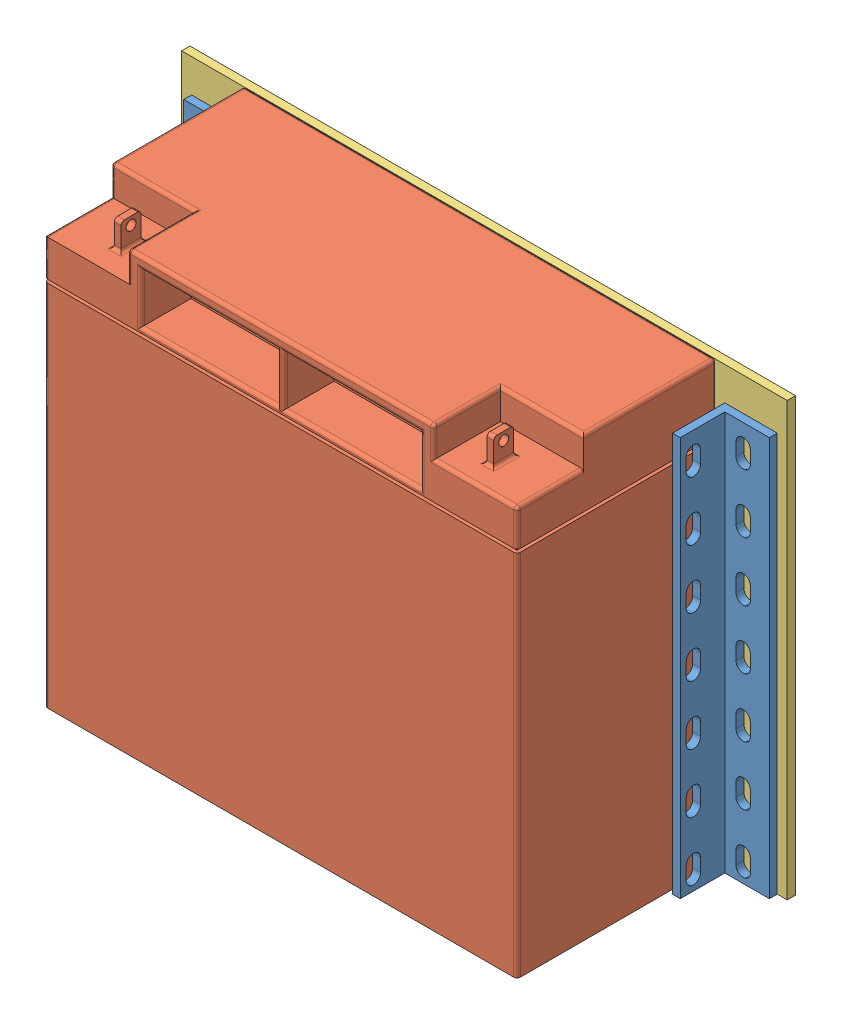
SolidWorks assembly 2018-204-Battery, configuration Default. Lengths in mm.
Overall size (231.14 167.13 80.9).
5 component instances, 4 part files, 12 mates.
Components (placement in the parent):
- 2018-204-D002-2: 2018-204-D002 [Default] at (124.5344 179.4934 45.2215) x (1 0 0) z (0 -1 0) size (20 20 152.4)
- 2018-100-D004-1: 2018-100-D004 [Default] at (32.7769 110.6594 46.7455) size (180.34 167.13 76.2)
- 2018-204-D002-5: 2018-204-D002 [Default] at (-58.9806 179.4934 45.2215) x (0 0 1) z (0 -1 0) size (20 20 152.4)
- 2018-204-D001-1: 2018-204-D001 [Default] at (148.3469 192.1934 45.2215) x (-1 0 0) z (0 0 -1) size (231.14 165.1 3.17)
- 2018-200-D033-1: 2018-200-D033 [Default] at (32.7769 180.7634 45.2215) size (92.74 20.32 13.35)
Mates (geometry in assembly coordinates):
- Coincident12: coincident: plane of 2018-100-D004-1 through (-57.3931 27.0934 122.9455) normal (0 -1 0); plane of 2018-204-D001-1 through (148.3469 27.0934 42.0465) normal (0 -1 0)
- Distance1: distance = 1.524 mm: plane of 2018-100-D004-1 through (32.7769 110.6594 46.7455) normal (0 0 -1); plane of 2018-204-D001-1 through (148.3469 192.1934 45.2215) normal (0 0 1)
- Width1: width: plane of 2018-100-D004-1 through (122.9469 27.0934 122.9455) normal (1 0 0); plane of 2018-100-D004-1 through (-57.3931 27.0934 122.9455) normal (-1 0 0); plane of 2018-204-D001-1 through (148.3469 192.1934 42.0465) normal (1 0 0); plane of 2018-204-D001-1 through (-82.7931 192.1934 42.0465) normal (-1 0 0)
- Coincident15: coincident: plane of 2018-204-D002-5 through (-126.8584 27.0934 45.2215) normal (0 0 -1); plane of 2018-204-D001-1 through (148.3469 192.1934 45.2215) normal (0 0 1)
- Coincident16: coincident: plane of 2018-204-D002-2 through (172.4122 27.0934 45.2215) normal (0 0 -1); plane of 2018-204-D001-1 through (148.3469 192.1934 45.2215) normal (0 0 1)
- Coincident17: coincident: plane of 2018-100-D004-1 through (-57.3931 27.0934 122.9455) normal (0 -1 0); plane of 2018-204-D002-5 through (-106.8584 27.0934 45.2215) normal (0 -1 0)
- Coincident18: coincident: plane of 2018-204-D002-2 through (172.4122 27.0934 45.2215) normal (0 -1 0); plane of 2018-100-D004-1 through (-57.3931 27.0934 122.9455) normal (0 -1 0)
- Coincident23: coincident: plane of 2018-204-D001-1 through (148.3469 192.1934 45.2215) normal (0 0 1); plane of 2018-200-D033-1 through (32.7769 180.7634 45.2215) normal (0 0 -1)
- Concentric1: concentric: cylinder of 2018-204-D001-1 through (68.9719 180.7634 42.0465) axis (0 0 -1) radius 3.3782; cylinder of 2018-200-D033-1 through (68.9719 180.7634 54.7465) axis (0 0 -1) radius 3.3782
- Parallel5: parallel: line of 2018-204-D001-1 through (-82.7931 192.1934 42.0465) axis (1 0 0); line of 2018-200-D033-1 through (77.5444 190.9234 45.2215) axis (-1 0 0)
- Width3: width: plane of 2018-204-D002-5 through (-58.9806 27.0934 45.2215) normal (1 0 0); plane of 2018-204-D002-2 through (124.5344 27.0934 65.2215) normal (-1 0 0); plane of 2018-100-D004-1 through (-57.3931 27.0934 122.9455) normal (-1 0 0); plane of 2018-100-D004-1 through (122.9469 27.0934 122.9455) normal (1 0 0)
- Distance3: distance = 183.515 mm: plane of 2018-204-D002-5 through (-58.9806 27.0934 45.2215) normal (1 0 0); plane of 2018-204-D002-2 through (124.5344 27.0934 65.2215) normal (-1 0 0)
